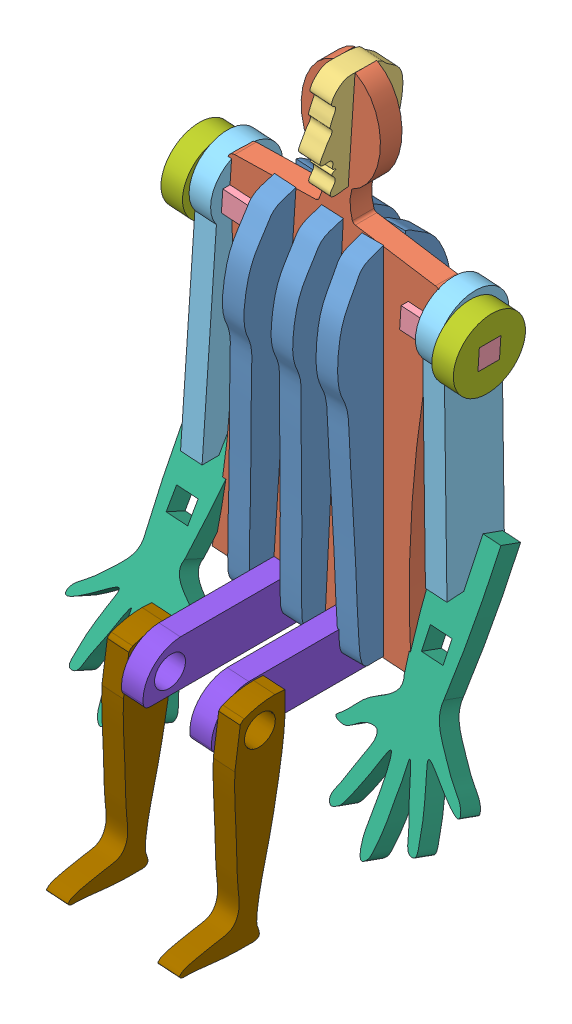
SolidWorks assembly Assem1, configuration Default. Lengths in mm.
Overall size (117.33 146.16 36.5).
17 component instances, 9 part files, 52 mates.
Components (placement in the parent):
- body.yz-4: body.yz [Default] at (-92.9346 34.1797 74.053) x (0 0 -1) z (0.997791 -0.066425 0) size (16.01 49.86 3)
- body-3: body [Default] at (-83.9772 40.7684 71.853) x (0.997791 -0.066425 0) z (0 0 1) size (108.32 139.27 3)
- body.yz-5: body.yz [Default] at (-79.6835 33.0741 74.053) x (0 0 -1) z (1 0 0) size (16.01 49.86 3)
- body.yz-6: body.yz [Default] at (-86.1167 33.6785 74.053) x (0 0 -1) z (0.998692 -0.051124 0) size (16.01 49.86 3)
- head.yz-6: head.yz [Default] at (-84.0059 62.9192 73.653) x (0 0 -1) z (0.997791 -0.066425 0) size (11.68 14.68 3)
- 肩膀關節-1: 肩膀關節 [Default] at (-69.5801 40.7953 70.853) x (0 0 1) z (0.066425 0.997791 0) size (5 9.9 3)
- 肩膀關節-2: 肩膀關節 [Default] at (-98.0444 45.6969 70.853) x (0 0 1) z (-0.066425 -0.997791 0) size (5 9.9 3)
- 手臂-3: 手臂 [Default] at (-66.4334 42.8993 72.703) x (-0.005208 -0.078233 0.996922) z (-0.997791 0.066425 0) size (10 38 3)
- 手-1: 手 [Default] at (-73.787 15.2384 66.7051) x (0.997791 -0.066425 0) z (0.023371 0.351069 0.936058) size (18.68 37.78 3)
- 肩膀關節卡榫-1: 肩膀關節卡榫 [Default] at (-66.4871 42.0927 73.353) x (0 0 -1) z (0.997791 -0.066425 0) size (10 10 3)
- 手-2: 手 [Default] at (-97.432 17.2598 71.4095) x (-0.997791 0.066425 0) z (-0.028174 -0.423219 -0.905589) size (18.68 37.78 3)
- 手臂-4: 手臂 [Default] at (-98.1197 44.5654 72.4699) x (0 0 1) z (-0.997791 0.066425 0) size (10 38 3)
- 肩膀關節卡榫-2: 肩膀關節卡榫 [Default] at (-101.1374 44.3994 73.353) x (0 0 1) z (-0.997791 0.066425 0) size (10 10 3)
- 大腿-1: 大腿 [Default] at (-79.4436 3.1971 69.853) x (0 0 1) z (-0.997791 0.066425 0) size (26.36 6.78 3)
- 大腿-2: 大腿 [Default] at (-88.9418 3.8295 69.853) x (0 0 1) z (-0.997791 0.066425 0) size (26.36 6.78 3)
- 小腿-1: 小腿 [Default] at (-76.4692 2.7135 88.8205) x (0.004412 0.066278 0.997791) z (-0.997791 0.066425 0) size (11.51 30.57 3)
- 小腿-2: 小腿 [Default] at (-91.9541 3.7444 88.8205) x (0.004412 0.066278 0.997791) z (-0.997791 0.066425 0) size (11.51 30.57 3)
Mates (geometry in assembly coordinates):
- Coincident21: coincident anti-aligned: plane of body.yz-4 through (-90.6526 23.2953 71.853) normal (0.066425 0.997791 0); plane of body-3 through (-90.6526 23.2953 74.853) normal (-0.066425 -0.997791 0)
- Coincident22: coincident anti-aligned: line of body.yz-4 through (-90.6526 23.2953 71.853) axis (0 0 1); line of body-3 through (-90.6526 23.2953 74.853) axis (0 0 -1)
- Coincident23: coincident anti-aligned: plane of body.yz-4 through (-90.6526 23.2953 74.853) normal (0 0 -1); plane of body-3 through (-82.6465 60.7579 74.853) normal (0 0 1)
- Coincident24: coincident anti-aligned: plane of body-3 through (-81.1687 60.3746 74.853) normal (0.066425 0.997791 0); plane of head.yz-6 through (-81.1687 60.3746 73.653) normal (-0.066425 -0.997791 0)
- Coincident25: coincident anti-aligned: plane of body-3 through (-82.6465 60.7579 74.853) normal (0 0 1); plane of head.yz-6 through (-81.0125 62.7199 74.853) normal (0 0 -1)
- Coincident26: coincident anti-aligned: line of body-3 through (-81.1687 60.3746 74.853) axis (0 0 -1); line of head.yz-6 through (-81.1687 60.3746 71.853) axis (0 0 1)
- Coincident27: coincident anti-aligned: plane of body-3 through (-82.6465 60.7579 74.853) normal (0 0 1); plane of body.yz-6 through (-83.6681 22.8303 74.853) normal (0 0 -1)
- Coincident28: coincident anti-aligned: line of body-3 through (-83.6681 22.8303 74.853) axis (0 0 -1); line of body.yz-6 through (-83.6681 22.8303 71.853) axis (0 0 1)
- Coincident29: coincident anti-aligned: plane of body-3 through (-82.6465 60.7579 74.853) normal (0 0 1); plane of body.yz-5 through (-76.6835 22.3654 74.853) normal (0 0 -1)
- Coincident30: coincident anti-aligned: line of body-3 through (-76.6835 22.3654 74.853) axis (0 0 -1); line of body.yz-5 through (-76.6835 22.3654 71.853) axis (0 0 1)
- Coincident31: coincident anti-aligned: plane of body-3 through (-71.9748 40.9547 74.853) normal (0.997791 -0.066425 0); plane of 肩膀關節-1 through (-71.7756 43.9481 71.853) normal (-0.997791 0.066425 0)
- Coincident32: coincident anti-aligned: line of body-3 through (-71.7756 43.9481 74.853) axis (0 0 -1); line of 肩膀關節-1 through (-71.7756 43.9481 71.853) axis (0 0 1)
- Coincident33: coincident anti-aligned: plane of body-3 through (-71.7756 43.9481 74.853) normal (-0.066425 -0.997791 0); plane of 肩膀關節-1 through (-69.3809 43.7887 70.853) normal (0.066425 0.997791 0)
- Coincident34: coincident anti-aligned: plane of body-3 through (-69.9793 40.8219 74.853) normal (0.066425 0.997791 0); plane of 肩膀關節-1 through (-69.5801 40.7953 70.853) normal (-0.066425 -0.997791 0)
- Coincident35: coincident anti-aligned: line of body-3 through (-71.9748 40.9547 74.853) axis (0 0 -1); line of 肩膀關節-1 through (-71.9748 40.9547 71.853) axis (0 0 1)
- Coincident36: coincident anti-aligned: plane of body-3 through (-71.9748 40.9547 74.853) normal (0.997791 -0.066425 0); plane of 肩膀關節-1 through (-71.7756 43.9481 71.853) normal (-0.997791 0.066425 0)
- Coincident37: coincident anti-aligned: plane of body-3 through (-82.6465 60.7579 71.853) normal (0 0 -1); plane of 肩膀關節-1 through (-71.7756 43.9481 71.853) normal (0 0 1)
- Coincident38: coincident anti-aligned: plane of body-3 through (-95.849 42.5441 74.853) normal (-0.997791 0.066425 0); plane of 肩膀關節-2 through (-95.849 42.5441 71.853) normal (0.997791 -0.066425 0)
- Coincident39: coincident anti-aligned: line of body-3 through (-95.849 42.5441 74.853) axis (0 0 -1); line of 肩膀關節-2 through (-95.849 42.5441 71.853) axis (0 0 1)
- Coincident40: coincident anti-aligned: plane of body-3 through (-82.6465 60.7579 71.853) normal (0 0 -1); plane of 肩膀關節-2 through (-95.849 42.5441 71.853) normal (0 0 1)
- Tangent11: tangent aligned: plane of 肩膀關節-1 through (-63.3941 43.3901 74.853) normal (0 0 1); cylinder of 手臂-3 through (-69.4268 43.0986 72.703) axis (0.997791 -0.066425 0) radius 2.15
- Coincident50: coincident anti-aligned: plane of 手臂-3 through (-71.0858 18.1779 82.0909) normal (-0.062178 -0.933991 0.351846); plane of 手-1 through (-73.8724 13.9567 70.3929) normal (0.062178 0.933991 -0.351846)
- Coincident51: coincident anti-aligned: plane of 手臂-3 through (-66.4334 42.8993 72.703) normal (0.997791 -0.066425 0); plane of 手-1 through (-68.2291 15.9263 69.5133) normal (-0.997791 0.066425 0)
- Coincident52: coincident anti-aligned: plane of 手臂-3 through (-69.789 37.658 58.1968) normal (0.023371 0.351069 0.936058); plane of 手-1 through (-73.787 15.2384 66.7051) normal (-0.023371 -0.351069 -0.936058)
- Coincident53: coincident aligned: plane of 肩膀關節-1 through (-63.3941 43.3901 71.853) normal (0.997791 -0.066425 0); plane of 肩膀關節卡榫-1 through (-63.4938 41.8934 73.353) normal (0.997791 -0.066425 0)
- Coincident55: coincident anti-aligned: plane of 肩膀關節-1 through (-63.3941 43.3901 71.853) normal (0 0 -1); plane of 肩膀關節卡榫-1 through (-63.3941 43.3901 71.853) normal (0 0 1)
- Coincident56: coincident anti-aligned: plane of 肩膀關節-1 through (-69.3809 43.7887 70.853) normal (0.066425 0.997791 0); plane of 肩膀關節卡榫-1 through (-63.3941 43.3901 74.853) normal (-0.066425 -0.997791 0)
- Coincident57: coincident aligned: plane of 肩膀關節-2 through (-104.2304 43.102 71.853) normal (-0.997791 0.066425 0); plane of 肩膀關節卡榫-2 through (-104.1308 44.5987 73.353) normal (-0.997791 0.066425 0)
- Coincident58: coincident anti-aligned: plane of 肩膀關節-2 through (-104.2304 43.102 71.853) normal (0 0 -1); plane of 肩膀關節卡榫-2 through (-104.0311 46.0954 71.853) normal (0 0 1)
- Coincident59: coincident anti-aligned: plane of 肩膀關節-2 through (-98.0444 45.6969 70.853) normal (0.066425 0.997791 0); plane of 肩膀關節卡榫-2 through (-104.0311 46.0954 71.853) normal (-0.066425 -0.997791 0)
- Coincident61: coincident anti-aligned: plane of 手臂-4 through (-101.1131 44.7646 72.4699) normal (-0.997791 0.066425 0); plane of 肩膀關節卡榫-2 through (-101.1374 44.3994 73.353) normal (0.997791 -0.066425 0)
- Coincident62: coincident anti-aligned: plane of 手-2 through (-97.6669 13.7312 69.7532) normal (0.060154 0.903589 -0.424155); plane of 手臂-4 through (-102.7181 20.6552 83.7872) normal (-0.060154 -0.903589 0.424155)
- Coincident63: coincident anti-aligned: plane of 手-2 through (-97.5165 15.9901 68.6928) normal (-0.028174 -0.423219 -0.905589); plane of 手臂-4 through (-101.5497 38.206 58.4359) normal (0.028174 0.423219 0.905589)
- Coincident64: coincident anti-aligned: line of 手-2 through (-100.0768 15.1669 72.4699) axis (-0.997791 0.066425 0); line of 手臂-4 through (-103.0702 15.3661 72.4699) axis (0.997791 -0.066425 0)
- Coincident65: coincident anti-aligned: line of 手-2 through (-100.1613 13.8972 69.7532) axis (-0.997791 0.066425 0); line of 手臂-4 through (-103.1547 14.0965 69.7532) axis (0.997791 -0.066425 0)
- Coincident67: coincident anti-aligned: plane of 手-2 through (-100.011 16.1562 68.6928) normal (-0.997791 0.066425 0); plane of 手臂-4 through (-98.1197 44.5654 72.4699) normal (0.997791 -0.066425 0)
- Coincident68: coincident anti-aligned: plane of body-3 through (-81.1994 -0.3051 74.853) normal (-0.066425 -0.997791 0); plane of 大腿-1 through (-82.6769 -0.2067 69.853) normal (0.066425 0.997791 0)
- Coincident69: coincident anti-aligned: plane of body-3 through (-82.6465 60.7579 74.853) normal (0 0 1); plane of 大腿-1 through (-82.437 3.3964 74.853) normal (0 0 -1)
- Tangent13: tangent: curve of body.yz-5; line of 大腿-1 through (-79.6835 -0.406 71.853) axis (0 0 1)
- Coincident71: coincident anti-aligned: plane of body-3 through (-88.1839 0.1599 74.853) normal (-0.066425 -0.997791 0); plane of 大腿-2 through (-92.1751 0.4256 69.853) normal (0.066425 0.997791 0)
- Coincident72: coincident anti-aligned: line of body-3 through (-92.1751 0.4256 74.853) axis (0 0 -1); line of 大腿-2 through (-92.1751 0.4256 71.853) axis (0 0 1)
- Coincident74: coincident anti-aligned: plane of 大腿-1 through (-79.4436 3.1971 69.853) normal (0.997791 -0.066425 0); plane of 小腿-1 through (-79.4626 2.9128 88.8205) normal (-0.997791 0.066425 0)
- Concentric6: concentric aligned: cylinder of 大腿-1 through (-82.6813 -0.2732 92.053) axis (0.997791 -0.066425 0) radius 2.15; cylinder of 小腿-1 through (-79.6879 -0.4725 92.053) axis (0.997791 -0.066425 0) radius 2.15
- Coincident75: coincident anti-aligned: plane of 大腿-2 through (-91.9352 4.0287 69.853) normal (-0.997791 0.066425 0); plane of 小腿-2 through (-91.9541 3.7444 88.8205) normal (0.997791 -0.066425 0)
- Concentric7: concentric aligned: cylinder of 大腿-2 through (-92.1795 0.3591 92.053) axis (0.997791 -0.066425 0) radius 2.15; cylinder of 小腿-2 through (-95.1729 0.5584 92.053) axis (0.997791 -0.066425 0) radius 2.15
- Coincident78: coincident anti-aligned: plane of 手臂-4 through (-101.1131 44.7646 72.4699) normal (-0.997791 0.066425 0); plane of 肩膀關節卡榫-2 through (-101.1374 44.3994 73.353) normal (0.997791 -0.066425 0)
- Coincident79: coincident anti-aligned: circle of 手臂-4; plane of 肩膀關節卡榫-2 through (-101.1374 44.3994 73.353) normal (0.997791 -0.066425 0)
- Coincident82: coincident anti-aligned: line of body-3 through (-88.1839 0.1599 71.853) axis (-0.997791 0.066425 0); line of 大腿-2 through (-92.1751 0.4256 71.853) axis (0.997791 -0.066425 0)
- Coincident83: coincident anti-aligned: plane of 手臂-4 through (-101.1131 44.7646 72.4699) normal (-0.997791 0.066425 0); plane of 肩膀關節卡榫-2 through (-101.1374 44.3994 73.353) normal (0.997791 -0.066425 0)
- Coincident84: coincident anti-aligned: plane of 肩膀關節-2 through (-98.2437 42.7035 74.853) normal (-0.997791 0.066425 0); plane of 手臂-4 through (-98.1197 44.5654 72.4699) normal (0.997791 -0.066425 0)
- Coincident86: coincident aligned: circle of 手臂-3; plane of 肩膀關節卡榫-1 through (-66.4871 42.0927 73.353) normal (-0.997791 0.066425 0)
- Parallel1: parallel anti-aligned: cylinder of 手臂-3 through (-69.4268 43.0986 72.703) axis (0.997791 -0.066425 0) radius 5; cylinder of 肩膀關節卡榫-1 through (-63.4938 41.8934 73.353) axis (-0.997791 0.066425 0) radius 5
